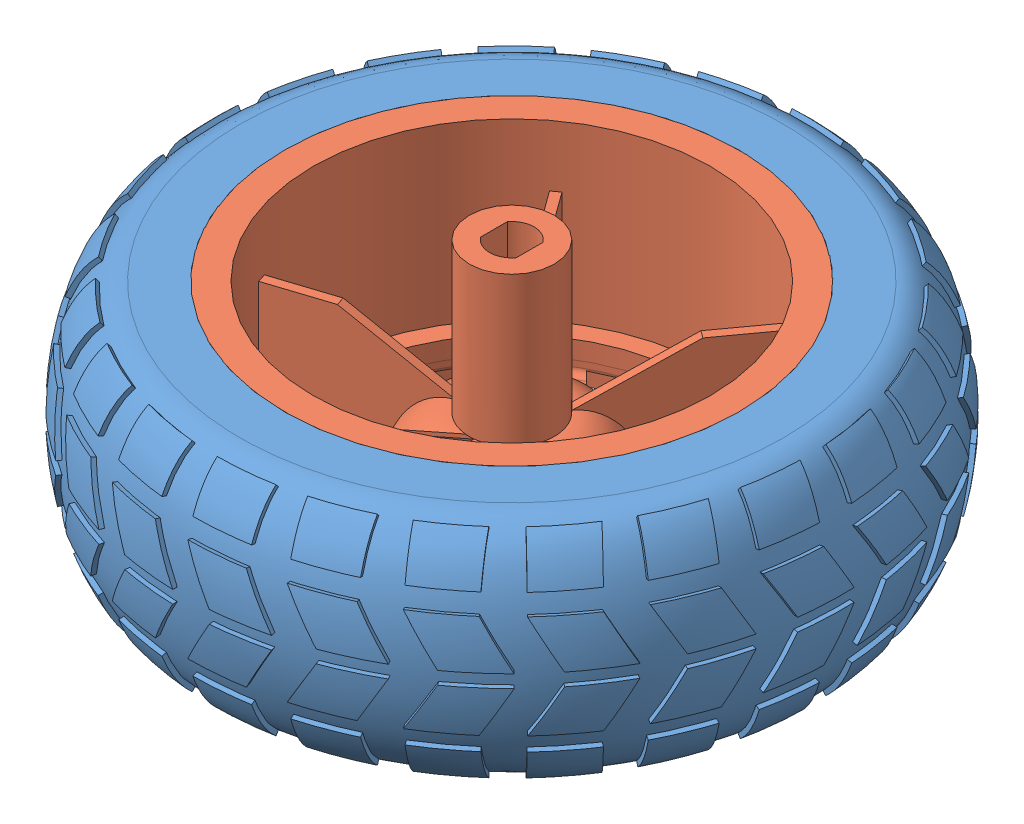
SolidWorks assembly Wheel Assembly, configuration Default. Lengths in mm.
Overall size (74.1 30.08 74.05).
2 component instances, 2 part files, 3 mates.
Components (placement in the parent):
- Tire-1: Tire [Default] at origin size (74.1 25.4 74.05)
- Wheel Hub-1: Wheel Hub [Default] x (1 0 0) z (0 -1 0) size (50.8 50.8 30.08)
Mates (geometry in assembly coordinates):
- Concentric1: concentric anti-aligned: circle of Tire-1; circle of Wheel Hub-1
- Coincident2: coincident aligned: plane of Tire-1 through (-25.4 12.7 0) normal (0 1 0); plane of Wheel Hub-1 through (0 12.7 0) normal (0 1 0)
- Coincident3: coordinate: point of Tire-1
